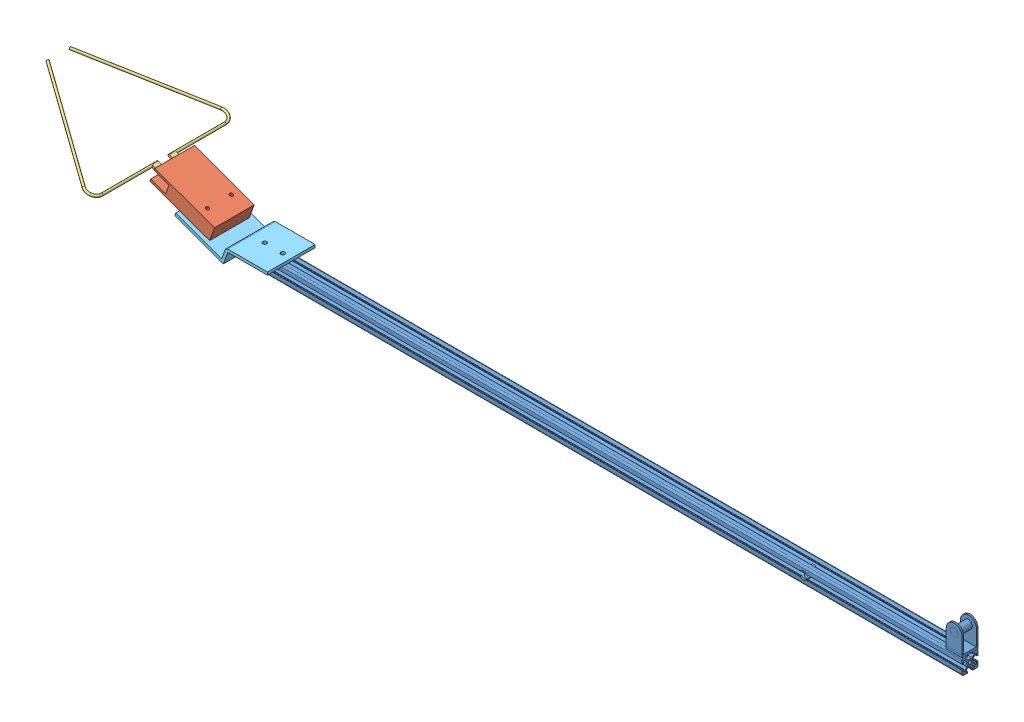
SolidWorks assembly gripper 22, configuration Default. Lengths in mm.
Overall size (1150.1 123.94 178.37).
7 component instances, 5 part files, 7 mates.
Components (placement in the parent):
- arm-1: arm [Default<As Machined>] at (854.8312 426.86 748.0498) size (900 53 20)
- gripper 1-1: gripper 1 [Default] at (-244.0948 417.4832 681.2305) x (0.939693 -0.34202 0) z (0 0 1) size (231.33 18 178.37) (flexible)
  - gripper base-1: gripper base [Default] at (16.831 37.4029 66.8193) size (80 18 55)
  - finger-1: finger [Default] at (-17.169 40.4029 73.8193) x (0 0 -1) z (1 0 0) size (92.18 3 165.33)
  - finger-2: finger [Default] at (-17.169 43.4029 59.8193) x (0 0 1) z (1 0 0) size (92.18 3 165.33)
  - gripper rod-1: gripper rod [Default] at (-6.169 48.4029 66.8193) x (0 0 1) z (1 0 0) size (6 11 22)
- clamp-1: clamp [Default] at (-155.6033 421.3536 778.0498) x (-0.939693 0.34202 0) z (0 0 -1) size (111.98 36.89 60)
Mates (geometry in assembly coordinates):
- Coincident2: coincident anti-aligned: plane of arm-1 through (-145.1688 436.8585 756.0498) normal (0 1 0); plane of clamp-1 through (-149.96 436.8585 778.0498) normal (0 -1 0)
- Width1: width anti-aligned: plane of arm-1 through (-145.1688 434.8585 758.0498) normal (0 0 1); plane of arm-1 through (-145.1688 434.8585 738.0498) normal (0 0 -1); plane of clamp-1 through (-154.4063 424.6425 718.0498) normal (0 0 -1); plane of clamp-1 through (-154.4063 424.6425 778.0498) normal (0 0 1)
- Concentric1: concentric aligned: cylinder of arm-1 through (-133.7641 405.2839 747.8686) axis (0 1 0) radius 2.5; cylinder of clamp-1 through (-133.7641 380.3585 747.8686) axis (0 1 0) radius 2.5
- Concentric2: concentric aligned: cylinder of arm-1 through (-110.7641 405.2839 747.8686) axis (0 1 0) radius 2.5; cylinder of clamp-1 through (-110.7641 380.3585 747.8686) axis (0 1 0) radius 2.5
- Concentric3: concentric aligned: cylinder of gripper-1/gripper base-1 through (-207.295 410.903 763.0498) axis (0.34202 0.939693 0) radius 2; cylinder of clamp-1 through (-217.2136 383.6519 763.0498) axis (0.34202 0.939693 0) radius 2
- Concentric4: concentric aligned: cylinder of gripper-1/gripper base-1 through (-207.295 410.903 733.0498) axis (0.34202 0.939693 0) radius 2; cylinder of clamp-1 through (-217.2136 383.6519 733.0498) axis (0.34202 0.939693 0) radius 2
- Coincident3: coincident anti-aligned: plane of gripper-1/gripper base-1 through (-215.4863 446.8738 748.0498) normal (-0.34202 -0.939693 0); plane of clamp-1 through (-154.4063 424.6425 778.0498) normal (0.34202 0.939693 0)
